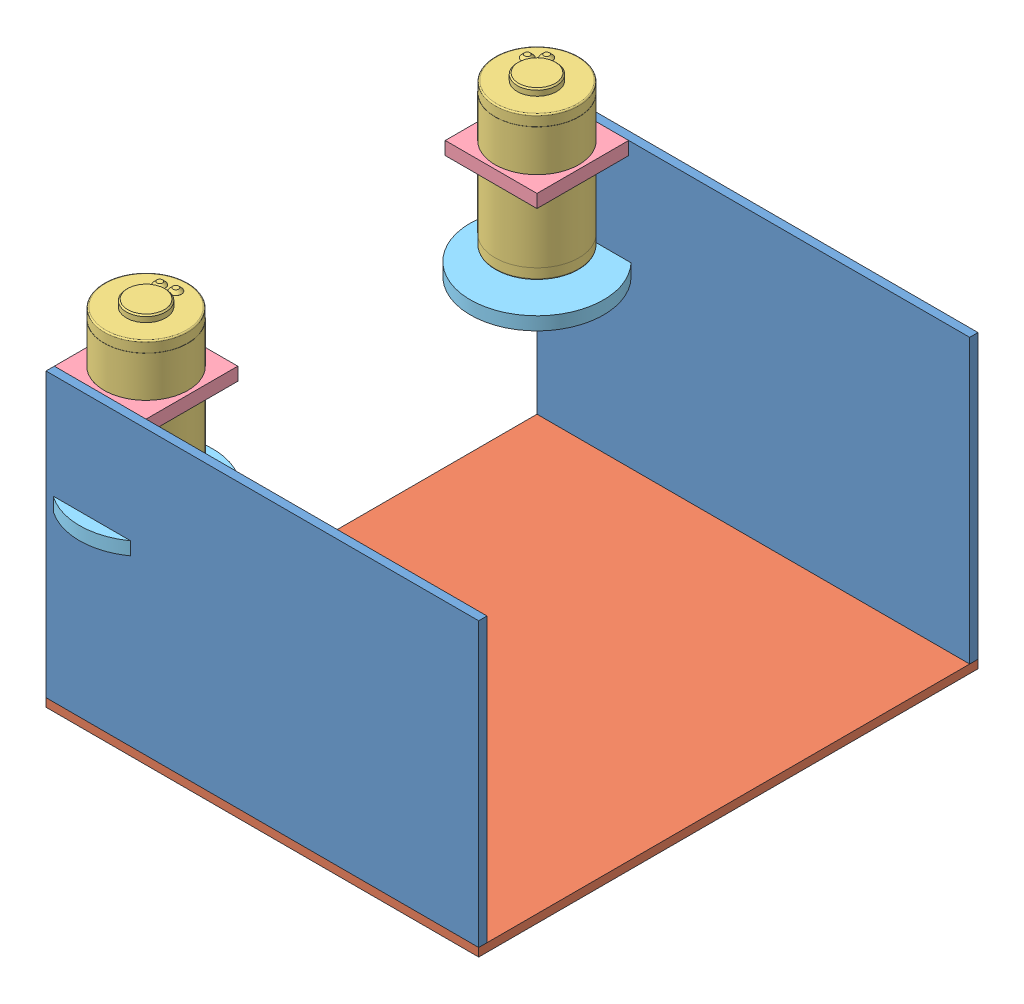
SolidWorks assembly ThrowerBoxShort-3580300, configuration Default. Lengths in mm.
Overall size (367.04 267.03 431.5).
9 component instances, 5 part files, 10 mates.
Components (placement in the parent):
- 3580307-1: 3580307 [Default] at (-82.1979 28.1204 24.2701) size (330.2 215.9 6.35)
- 3580307-2: 3580307 [Default] at (-82.1979 28.1204 -350.3799) x (-1 0 0) z (0 0 -1) size (330.2 215.9 6.35)
- 3580305-4: 3580305 [Default] at (-82.1979 -83.0046 -163.0549) x (1 0 0) z (0 -1 0) size (330.2 381 6.35)
- CIM-217-2000-3580300-1: CIM-217-2000-3580300 [Default] at (-212.2979 65.8041 -13.9049) x (0 1 0) z (-0.556008 0 0.831177) size (150.2 64.01 64.01)
- cim_mount-3580300-1: cim_mount-3580300 [Default] at (-212.2979 126.0704 -13.9049) size (70 10 70)
- cim_mount-3580300-2: cim_mount-3580300 [Default] at (-212.2979 126.0704 -312.2049) size (70 10 70)
- 4inwheel-3580300-1: 4inwheel-3580300 [Default] at (-212.2979 46.1084 -312.2049) x (-0.236097 0 -0.971729) z (0.971729 0 -0.236097) size (101.6 10 101.6)
- 4inwheel-3580300-2: 4inwheel-3580300 [Default] at (-212.2979 46.1084 -13.9049) x (0.713797 0 0.700352) z (-0.700352 0 0.713797) size (101.6 10 101.6)
- CIM-217-2000-3580300-4: CIM-217-2000-3580300 [Default] at (-212.2979 66.2483 -312.2049) x (0 1 0) z (0 0 1) size (150.2 64.01 64.01)
Mates (geometry in assembly coordinates):
- Coincident3: coincident aligned: plane of 3580307-1 through (-82.1979 28.1204 27.4451) normal (0 0 1); plane of 3580305-4 through (-247.2979 -86.1796 27.4451) normal (0 0 1)
- Coincident4: coincident aligned: plane of 3580307-2 through (-82.1979 28.1204 -353.5549) normal (0 0 -1); plane of 3580305-4 through (-247.2979 -86.1796 -353.5549) normal (0 0 -1)
- Coincident6: coincident anti-aligned: plane of 3580307-2 through (-82.1979 28.1204 -347.2049) normal (0 0 1); plane of cim_mount-3580300-2 through (-247.2979 136.0704 -347.2049) normal (0 0 -1)
- Coincident7: coincident anti-aligned: line of 3580307-2 through (-247.2979 136.0704 -347.2049) axis (1 0 0); line of cim_mount-3580300-2 through (-177.2979 136.0704 -347.2049) axis (-1 0 0)
- Coincident9: coincident anti-aligned: line of 3580307-2 through (-247.2979 -79.8296 -347.2049) axis (0 1 0); line of cim_mount-3580300-2 through (-247.2979 136.0704 -347.2049) axis (0 -1 0)
- Concentric1: concentric aligned: circle of 4inwheel-3580300-1; cylinder of CIM-217-2000-3580300-4 through (-212.2979 30.6483 -312.2049) axis (0 1 0) radius 4
- Parallel4: parallel aligned: plane of CIM-217-2000-3580300-1 through (-224.7961 180.4041 -22.2655) normal (0 1 0); plane of CIM-217-2000-3580300-4 through (-227.3347 180.8483 -312.2049) normal (0 1 0)
- Parallel5: parallel aligned: plane of CIM-217-2000-3580300-1 through (-212.2979 30.2041 -13.9049) normal (0 -1 0); plane of CIM-217-2000-3580300-4 through (-212.2979 30.6483 -312.2049) normal (0 -1 0)
- Lock4: lock: unknown of CIM-217-2000-3580300-1; unknown of 4inwheel-3580300-2
- Coincident22: coincident aligned: plane of 4inwheel-3580300-1 through (-212.2979 46.1084 -312.2049) normal (0 -1 0); plane of 4inwheel-3580300-2 through (-212.2979 46.1084 -13.9049) normal (0 -1 0)
